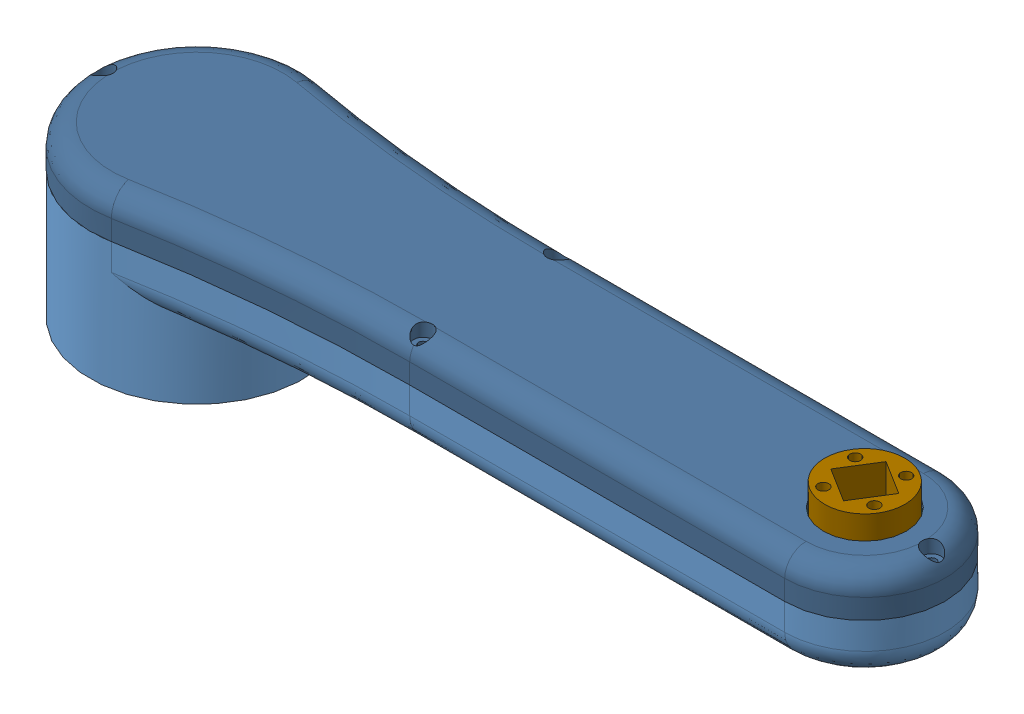
SolidWorks assembly upper limb assembly, configuration Default. Lengths in mm.
Overall size (320 71.8 80).
13 component instances, 10 part files, 28 mates.
Components (placement in the parent):
- upper limb v4-1: upper limb v4 [Default] at (0.3187 172.8353 234.9828) size (320 47.8 80)
- MAD5008IPE-1: MAD5008IPE [Default] at (0.3187 147.0353 234.9828) size (56 29.3 56)
- GT2 15 Teeth motor upper limb-1: GT2 15 Teeth motor upper limb [Default] at (0.3187 174.4507 234.9828) size (24 28 24)
- 15_45 pulley-1: 15_45 pulley [Default] at (108.3058 199.9066 223.9107) x (-0.827218 0 0.561881) z (0.561881 0 0.827218) size (34 30.5 34)
- W_617_8-1: W_617_8 [Default] at (109.9187 170.3353 234.9828) x (0 1 0) z (0.105818 0 0.994386) size (2.5 14.75 14.75)
- W_61706_2RZ-1: W_61706_2RZ [Default] at (250.3187 174.3353 234.9828) x (0 -1 0) z (0 0 1) size (4 46.12 46.12)
- encoder-1: encoder [Default] at (0.3187 191.6053 234.9828) x (0.010998 0 -0.99994) z (0 1 0) size (28.79 43.54 9.21)
- encoder holder-1: encoder holder [Default] at (0.3187 182.8353 234.9828) x (0 0 -1) z (1 0 0) size (70 5 40.98)
- knee joint 45T-1: knee joint 45T [Default] at (250.3187 183.8353 234.9828) x (-0.529512 0 0.848303) z (-0.848303 0 -0.529512) size (34 41.5 34)
- upper limb cover v4-1: upper limb cover v4 [Default] at (0.3187 198.3353 234.9828) x (1 0 0) z (0 0 -1) size (320 15.79 80)
- W_617_8-2: W_617_8 [Default] at (109.9187 198.3353 234.9828) x (0 1 0) z (0.105818 0 0.994386) size (2.5 14.75 14.75)
- W_617_8-3: W_617_8 [Default] at (0.3187 198.3353 234.9828) x (0 1 0) z (0.933414 0 0.358801) size (2.5 14.75 14.75)
- W_61706_2RZ-2: W_61706_2RZ [Default] at (250.3187 200.8353 234.9828) x (0 -1 0) z (0 0 1) size (4 46.12 46.12)
Mates (geometry in assembly coordinates):
- Concentric1: concentric: cylinder of upper limb v4-1 through (0.3187 187.8353 234.9828) axis (0 -1 0) radius 30; cylinder of MAD5008IPE-1 through (0.3187 172.8353 234.9828) axis (0 -1 0) radius 28
- Coincident1: coincident: plane of upper limb v4-1 through (0.3187 172.8353 234.9828) normal (0 1 0); plane of MAD5008IPE-1 through (0.3187 172.8353 234.9828) normal (0 1 0)
- Concentric4: concentric: cylinder of MAD5008IPE-1 through (0.3187 169.8353 227.4828) axis (0 1 0) radius 1.5; cylinder of GT2 15 Teeth motor upper limb-1 through (0.3187 172.8353 227.4828) axis (0 1 0) radius 1.5
- Concentric5: concentric: cylinder of MAD5008IPE-1 through (0.3187 169.8353 242.4828) axis (0 1 0) radius 1.5; cylinder of GT2 15 Teeth motor upper limb-1 through (0.3187 172.8353 242.4828) axis (0 1 0) radius 1.5
- Coincident3: coincident: plane of MAD5008IPE-1 through (0.3187 172.8353 234.9828) normal (0 1 0); plane of GT2 15 Teeth motor upper limb-1 through (-11.6813 172.8353 234.9828) normal (0 -1 0)
- Concentric6: concentric: cylinder of upper limb v4-1 through (109.9187 167.8353 234.9828) axis (0 1 0) radius 6; cylinder of 15_45 pulley-1 through (109.9187 174.8353 234.9828) axis (0 1 0) radius 17
- Coincident5: coincident: plane of GT2 15 Teeth motor upper limb-1 through (-4.4559 176.8353 234.9828) normal (0 1 0); plane of 15_45 pulley-1 through (109.9187 176.8353 234.9828) normal (0 1 0)
- Concentric7: concentric: cylinder of upper limb v4-1 through (109.9187 167.8353 234.9828) axis (0 1 0) radius 6; cylinder of W_617_8-1 through (109.9187 172.8353 234.9828) axis (0 1 0) radius 6
- Coincident6: coincident: plane of upper limb v4-1 through (0.3187 172.8353 234.9828) normal (0 1 0); plane of W_617_8-1 through (105.792 172.8353 235.422) normal (0 1 0)
- Concentric8: concentric: cylinder of upper limb v4-1 through (250.3187 167.8353 234.9828) axis (0 1 0) radius 18.5; cylinder of W_61706_2RZ-1 through (250.3187 124.3353 234.9828) axis (0 -1 0) radius 18.5
- Coincident8: coincident: plane of upper limb v4-1 through (250.3187 170.3353 234.9828) normal (0 1 0); plane of W_61706_2RZ-1 through (265.5187 170.3353 234.9828) normal (0 -1 0)
- Concentric10: concentric: cylinder of upper limb v4-1 through (0.3187 187.8353 234.9828) axis (0 -1 0) radius 30; cylinder of encoder holder-1 through (0.3187 187.8353 234.9828) axis (0 -1 0) radius 30
- Coincident9: coincident: plane of upper limb v4-1 through (9.9018 182.8353 202.84) normal (-0.285714 0 0.958315); plane of encoder holder-1 through (9.9018 187.8353 202.84) normal (0.285714 0 -0.958315)
- Coincident10: coincident: plane of upper limb v4-1 through (0.3187 182.8353 234.9828) normal (0 1 0); plane of encoder holder-1 through (0.3187 182.8353 234.9828) normal (0 -1 0)
- Coincident11: coincident: plane of encoder-1 through (28.2061 187.8353 249.6777) normal (0 -1 0); plane of encoder holder-1 through (0.3187 187.8353 234.9828) normal (0 1 0)
- Concentric11: concentric: cylinder of W_61706_2RZ-1 through (250.3187 124.3353 234.9828) axis (0 -1 0) radius 15; cylinder of knee joint 45T-1 through (250.3187 183.8353 234.9828) axis (0 1 0) radius 17
- Coincident13: coincident: plane of 15_45 pulley-1 through (113.8684 194.8353 232.3001) normal (0 -1 0); plane of knee joint 45T-1 through (250.3187 194.8353 234.9828) normal (0 -1 0)
- Coincident14: coincident: plane of upper limb v4-1 through (0.3187 187.8353 234.9828) normal (0 1 0); plane of upper limb cover v4-1 through (0.3187 187.8353 234.9828) normal (0 -1 0)
- Concentric12: concentric: cylinder of upper limb cover v4-1 through (109.9187 203.3353 234.9828) axis (0 -1 0) radius 6; cylinder of W_617_8-2 through (109.9187 200.8353 234.9828) axis (0 1 0) radius 6
- Coincident15: coincident: plane of upper limb cover v4-1 through (109.9187 200.8353 234.9828) normal (0 -1 0); plane of W_617_8-2 through (105.792 200.8353 235.422) normal (0 1 0)
- Concentric13: concentric: cylinder of GT2 15 Teeth motor upper limb-1 through (0.3187 174.5216 234.9828) axis (0 1 0) radius 4; cylinder of encoder-1 through (0.3187 191.9585 234.9828) axis (0 1 0) radius 2
- Concentric14: concentric: cylinder of upper limb cover v4-1 through (0.3187 203.3353 234.9828) axis (0 -1 0) radius 6; cylinder of W_617_8-3 through (0.3187 200.8353 234.9828) axis (0 1 0) radius 6
- Coincident16: coincident: plane of upper limb cover v4-1 through (0.3187 200.8353 234.9828) normal (0 -1 0); plane of W_617_8-3 through (-1.1703 200.8353 238.8565) normal (0 1 0)
- Concentric15: concentric: cylinder of upper limb cover v4-1 through (250.3187 203.3353 234.9828) axis (0 -1 0) radius 18.5; cylinder of W_61706_2RZ-2 through (250.3187 150.8353 234.9828) axis (0 -1 0) radius 18.5
- Coincident17: coincident: plane of upper limb cover v4-1 through (250.3187 200.8353 234.9828) normal (0 -1 0); plane of W_61706_2RZ-2 through (266.452 200.8353 234.9828) normal (0 1 0)
- Concentric16: concentric: cylinder of 15_45 pulley-1 through (109.9187 200.8353 234.9828) axis (0 -1 0) radius 4; cylinder of W_617_8-2 through (109.9187 248.3353 234.9828) axis (0 1 0) radius 4
- Concentric17: concentric: cylinder of knee joint 45T-1 through (250.3187 211.8353 234.9828) axis (0 -1 0) radius 15; cylinder of W_61706_2RZ-2 through (250.3187 150.8353 234.9828) axis (0 -1 0) radius 15
- Concentric18: concentric: cylinder of upper limb v4-1 through (0.3187 187.8353 249.9828) axis (0 -1 0) radius 1.5; cylinder of MAD5008IPE-1 through (0.3187 150.0353 249.9828) axis (0 -1 0) radius 1.5
